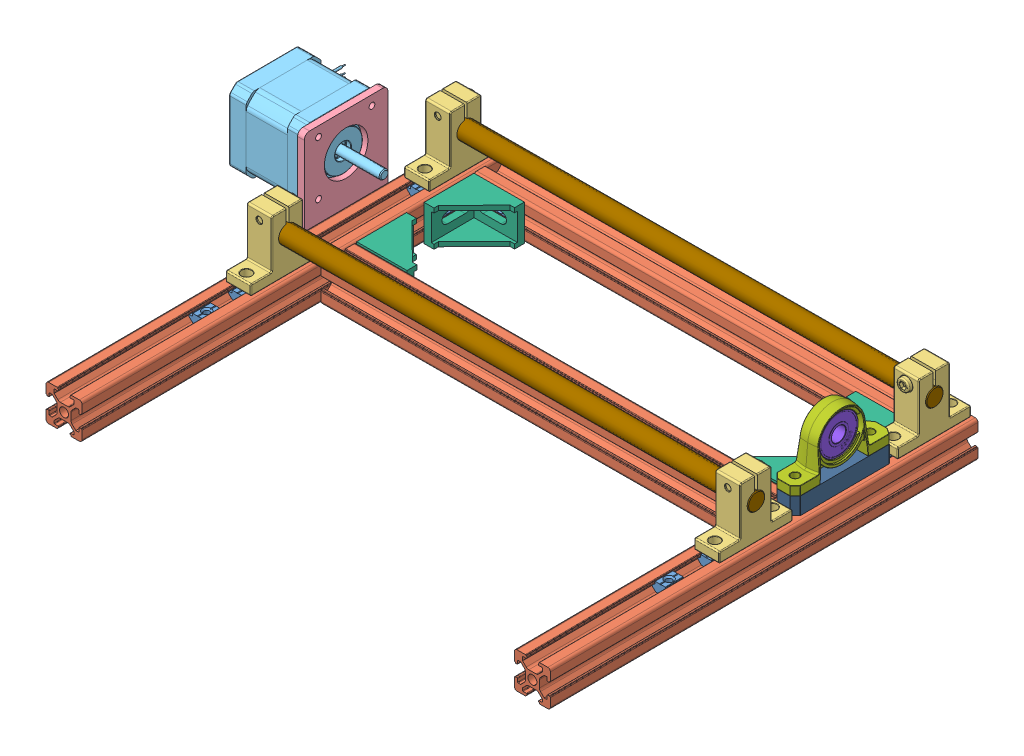
SolidWorks assembly Portal, configuration Default. Lengths in mm.
Overall size (325.5 70.93 241.56).
46 component instances, 10 part files, 48 mates.
Components (placement in the parent):
- Portal left-1: Portal left [Default] at (-77.4247 133.5164 88.3401) size (65.98 66.45 240.11) (flexible)
  - Slider T-Nut for 2020 - M4-1: Slider T-Nut for 2020 - M4 [Default] at (131.9435 -515.0191 -56.8758) x (0 -1 0) z (-0.005599 0 -0.999984) size (10 5 10)
  - Slider T-Nut for 2020 - M4-2: Slider T-Nut for 2020 - M4 [Default] at (132.0825 -515.0191 -32.0562) x (0 -1 0) z (-0.005599 0 -0.999984) size (10 5 10)
  - Slider T-Nut for 2020 - M4-3: Slider T-Nut for 2020 - M4 [Default] at (131.4239 -516.3614 -88.5284) x (0.999984 0 -0.005599) z (0.005599 0 0.999984) size (10 5 10)
  - Slider T-Nut for 2020 - M4-4: Slider T-Nut for 2020 - M4 [Default] at (131.9846 -516.3614 11.6) x (0.999984 0 -0.005599) z (0.005599 0 0.999984) size (10 5 10)
  - Slider T-Nut for 2020 - M4-5: Slider T-Nut for 2020 - M4 [Default] at (131.2447 -516.3614 -120.5279) x (0.999984 0 -0.005599) z (0.005599 0 0.999984) size (10 5 10)
  - Slider T-Nut for 2020 - M4-6: Slider T-Nut for 2020 - M4 [Default] at (141.946 -516.3614 -10.4561) x (-0.999984 0 0.005599) z (-0.005599 0 -0.999984) size (10 5 10)
  - Slider T-Nut for 2020 - M4-7: Slider T-Nut for 2020 - M4 [Default] at (141.1467 -515.0191 -92.0522) x (0 -1 0) z (0.005599 0 0.999984) size (10 5 10)
  - Slider T-Nut for 2020 - M4-8: Slider T-Nut for 2020 - M4 [Default] at (141.3587 -515.0191 -54.1911) x (0 -1 0) z (0.005599 0 0.999984) size (10 5 10)
  - 2020-2: 2020 [Default] at (136.2844 -519.7614 -121.0254) x (0.999984 0 -0.005599) z (0.005599 0 0.999984) size (20 20 240)
  - SK8 SC8UU LINEAR RAIL ORIGINAL-1: SK8 SC8UU LINEAR RAIL ORIGINAL [Valor predeterminado] at (129.4547 -493.4614 -99.5175) x (-0.005599 0 -0.999984) z (0.999984 0 -0.005599) size (41.13 32.6 13.92)
  - SK8 SC8UU LINEAR RAIL ORIGINAL-2: SK8 SC8UU LINEAR RAIL ORIGINAL [Valor predeterminado] at (130.0154 -493.4614 0.6109) x (-0.005599 0 -0.999984) z (0.999984 0 -0.005599) size (41.13 32.6 13.92)
  - Nema_17_Holder-1: Nema_17_Holder [Default] at (123.0455 -480.2144 -38.6381) x (0 -1 0) z (0.005599 0 0.999984) size (65 3.7 47)
  - nema_17_motor-1: nema_17_motor [Varsayılan] at (122.9852 -484.3114 -49.4155) x (0 -1 0) z (0.999984 0 -0.005599) size (42 58.5 65.65)
  - Slider T-Nut for 2020 - M4-9: Slider T-Nut for 2020 - M4 [Default] at (142.2497 -516.3614 43.7873) x (-0.999984 0 0.005599) z (-0.005599 0 -0.999984) size (10 5 10)
  - Slider T-Nut for 2020 - M4-10: Slider T-Nut for 2020 - M4 [Default] at (141.3398 -523.2614 -118.7171) x (-0.999984 0 0.005599) z (0.005599 0 0.999984) size (10 5 10)
- 2020-1: 2020 [Default] at (68.9155 -386.245 -22.7415) x (-0.005599 0 -0.999984) z (0.999984 0 -0.005599) size (20 20 240)
- 2020-2: 2020 [Default] at (69.3963 -386.845 63.1189) x (0.005599 0 0.999984) z (0.999984 0 -0.005599) size (20 20 240)
- Slider T-Nut for 2020 - M4-1: Slider T-Nut for 2020 - M4 [Default] at (299.9382 -381.5026 -19.335) x (0 -1 0) z (-0.999984 0 0.005599) size (10 5 10)
- Slider T-Nut for 2020 - M4-2: Slider T-Nut for 2020 - M4 [Default] at (87.9416 -381.5026 -18.1479) x (0 -1 0) z (-0.999984 0 0.005599) size (10 5 10)
- Slider T-Nut for 2020 - M4-3: Slider T-Nut for 2020 - M4 [Default] at (78.3699 -381.5026 58.3686) x (0 -1 0) z (0.999984 0 -0.005599) size (10 5 10)
- Slider T-Nut for 2020 - M4-4: Slider T-Nut for 2020 - M4 [Default] at (290.3665 -381.5026 57.1815) x (0 -1 0) z (0.999984 0 -0.005599) size (10 5 10)
- angle bracket 20x20-1: angle bracket 20x20 [Default] at (68.9715 -396.545 -12.7416) x (0.005599 0 0.999984) z (0 1 0) size (29 29 20)
- angle bracket 20x20-2: angle bracket 20x20 [Default] at (308.9678 -376.545 -14.0855) x (0.005599 0 0.999984) z (0 -1 0) size (29 29 20)
- angle bracket 20x20-3: angle bracket 20x20 [Default] at (69.3403 -376.545 53.119) x (-0.005599 0 -0.999984) z (0 -1 0) size (29 29 20)
- angle bracket 20x20-4: angle bracket 20x20 [Default] at (309.3366 -396.545 51.7752) x (-0.005599 0 -0.999984) z (0 1 0) size (29 29 20)
- Portal right-1: Portal right [Default] at (324.1953 -378.3552 77.9841) x (0.999984 0 -0.005599) z (0.005599 0 0.999984) size (20 70.33 240) (flexible)
  - 2020-1: 2020 [Default] at (-4.7118 -7.8898 -112.1535) size (20 20 240)
  - Slider T-Nut for 2020 - M4-1: Slider T-Nut for 2020 - M4 [Default] at (-9.7541 -2.9898 -24.6192) size (10 5 10)
  - Slider T-Nut for 2020 - M4-2: Slider T-Nut for 2020 - M4 [Default] at (-9.7541 -2.9898 -79.6842) size (10 5 10)
  - Slider T-Nut for 2020 - M4-3: Slider T-Nut for 2020 - M4 [Default] at (-9.4118 -3.1474 -35.2918) x (0 -1 0) z (0 0 -1) size (10 5 10)
  - Slider T-Nut for 2020 - M4-4: Slider T-Nut for 2020 - M4 [Default] at (-9.4118 -3.1474 -73.1535) x (0 -1 0) z (0 0 -1) size (10 5 10)
  - Slider T-Nut for 2020 - M4-5: Slider T-Nut for 2020 - M4 [Default] at (-9.7541 -2.9898 -66.6192) size (10 5 10)
  - Slider T-Nut for 2020 - M4-6: Slider T-Nut for 2020 - M4 [Default] at (-9.7541 -2.9898 -111.6842) size (10 5 10)
  - Slider T-Nut for 2020 - M4-7: Slider T-Nut for 2020 - M4 [Default] at (-9.7541 -2.9898 -11.5542) size (10 5 10)
  - Slider T-Nut for 2020 - M4-8: Slider T-Nut for 2020 - M4 [Default] at (-9.7541 -2.9898 20.4458) size (10 5 10)
  - Slider T-Nut for 2020 - M4-9: Slider T-Nut for 2020 - M4 [Default] at (-9.7541 -2.9898 46.1413) size (10 5 10)
  - Slider T-Nut for 2020 - M4-10: Slider T-Nut for 2020 - M4 [Default] at (-9.7541 -12.8898 -7.907) x (1 0 0) z (0 0 -1) size (10 5 10)
  - SK8 SC8UU LINEAR RAIL ORIGINAL-1: SK8 SC8UU LINEAR RAIL ORIGINAL [Valor predeterminado] at (-11.6618 18.4102 9.4458) x (0 0 -1) z (1 0 0) size (41.13 32.6 13.92)
  - SK8 SC8UU LINEAR RAIL ORIGINAL-2: SK8 SC8UU LINEAR RAIL ORIGINAL [Valor predeterminado] at (2.2382 18.4102 -90.6842) x (0 0 1) z (-1 0 0) size (41.13 32.6 13.92)
  - KP08-1: KP08 [Default] at (-4.7118 11.5602 -42.9091) x (0 0 1) z (-1 0 0) size (55 40.88 13.92)
    - KP08-2: KP08 [По умолчанию] at (2.2899 16 0) size (55 40.88 13.13)
    - 608RS-2: 608RS [Default] at (2.2899 16 -3.5) x (0.16403 0.986455 0) z (0 0 1) size (22 22 10.85)
- Shaft-1: Shaft [8mm (Default)] at (152.0285 -356.235 -11.7374) x (0.000031 0.999984 0.005599) z (0.005599 -0.005599 0.999969) size (10 274.31 10)
- Shaft-2: Shaft [8mm (Default)] at (226.8954 -356.235 87.9749) x (0.000031 -0.999984 0.005599) z (0.005599 0.005599 0.999969) size (10 274.31 10)
- stand-1: stand [Default] at (319.2562 -366.795 37.392) x (-0.005599 0 -0.999984) z (0 -1 0) size (55 13 9.45)
Mates (geometry in assembly coordinates):
- Coincident1: coincident aligned: plane of 2020-1 through (68.9615 -386.245 -14.5416) normal (0.005599 0 0.999984); plane of Slider T-Nut for 2020 - M4-1 through (299.9578 -391.345 -15.8351) normal (0.005599 0 0.999984)
- Coincident2: coincident aligned: plane of 2020-1 through (68.9615 -386.245 -14.5416) normal (0.005599 0 0.999984); plane of Slider T-Nut for 2020 - M4-2 through (87.9612 -391.345 -14.648) normal (0.005599 0 0.999984)
- Coincident3: coincident: plane of 2020-1 through (68.9155 -386.545 -22.7415) normal (0 1 0); line of Slider T-Nut for 2020 - M4-1 through (299.9646 -386.545 -14.6351) axis (-0.999984 0 0.005599)
- Coincident4: coincident: plane of 2020-1 through (68.9155 -386.545 -22.7415) normal (0 1 0); line of Slider T-Nut for 2020 - M4-2 through (87.9679 -386.545 -13.448) axis (-0.999984 0 0.005599)
- Coincident5: coincident aligned: plane of 2020-2 through (69.3504 -386.845 54.919) normal (-0.005599 0 -0.999984); plane of Slider T-Nut for 2020 - M4-3 through (78.3503 -383.345 54.8686) normal (-0.005599 0 -0.999984)
- Coincident6: coincident aligned: plane of 2020-2 through (69.3504 -386.845 54.919) normal (-0.005599 0 -0.999984); plane of Slider T-Nut for 2020 - M4-4 through (290.3469 -383.345 53.6815) normal (-0.005599 0 -0.999984)
- Coincident7: coincident: plane of 2020-2 through (69.3963 -386.545 63.1189) normal (0 -1 0); line of Slider T-Nut for 2020 - M4-4 through (290.3402 -386.545 52.4815) axis (0.999984 0 -0.005599)
- Coincident8: coincident: plane of 2020-2 through (69.3963 -386.545 63.1189) normal (0 -1 0); line of Slider T-Nut for 2020 - M4-3 through (78.3436 -386.545 53.6686) axis (0.999984 0 -0.005599)
- Coincident21: coincident aligned: plane of Portal left-1/2020-2 through (64.7596 -388.5559 -32.7184) normal (-0.005599 0 -0.999984); plane of 2020-1 through (308.8558 -377.745 -34.0852) normal (-0.005599 0 -0.999984)
- Coincident26: coincident aligned: plane of 2020-1 through (308.8558 -377.745 -34.0852) normal (-0.005599 0 -0.999984); plane of Portal right-1/2020-1 through (324.7555 -388.5559 -34.1742) normal (-0.005599 0 -0.999984)
- Coincident30: coincident aligned: plane of Portal left-1/2020-2 through (23.7593 143.0852 331.2674) normal (0 1 0); plane of 2020-2 through (269.8593 143.0852 185.7674) normal (0 1 0)
- LimitDistance1: limit distance = 9 mm aligned: plane of Slider T-Nut for 2020 - M4-3 through (78.3559 -386.545 55.8686) normal (-0.999984 0 0.005599); plane of 2020-2 through (69.4294 -384.5341 69.0188) normal (-0.999984 0 0.005599)
- LimitDistance2: limit distance = 202 mm anti-aligned: plane of Slider T-Nut for 2020 - M4-4 through (290.3525 -386.545 54.6815) normal (-0.999984 0 0.005599); plane of Slider T-Nut for 2020 - M4-3 through (88.3557 -386.545 55.8126) normal (0.999984 0 -0.005599)
- LimitDistance3: limit distance = 9 mm aligned: plane of Slider T-Nut for 2020 - M4-4 through (300.3524 -386.545 54.6255) normal (0.999984 0 -0.005599); plane of 2020-2 through (309.4256 -384.5341 67.6749) normal (0.999984 0 -0.005599)
- Coincident32: coincident anti-aligned: plane of 2020-2 through (309.3366 -378.345 51.7752) normal (-0.005599 0 -0.999984); plane of angle bracket 20x20-4 through (309.3366 -376.545 51.7752) normal (0.005599 0 0.999984)
- Slot1: slot anti-aligned: cylinder of Slider T-Nut for 2020 - M4-4 through (295.3539 -386.545 54.9035) axis (0.005599 0 0.999984) radius 1.666; plane of angle bracket 20x20-4 through (290.4326 -389.545 68.9693) normal (0 1 0); cylinder of angle bracket 20x20-4 through (300.4324 -386.545 68.9133) axis (-0.005599 0 -0.999984) radius 3
- Coincident33: coincident anti-aligned: plane of 2020-2 through (309.3366 -378.345 51.7752) normal (-0.005599 0 -0.999984); plane of angle bracket 20x20-3 through (69.3403 -396.545 53.119) normal (0.005599 0 0.999984)
- Slot2: slot anti-aligned: cylinder of Slider T-Nut for 2020 - M4-3 through (83.3572 -386.545 56.0906) axis (0.005599 0 0.999984) radius 1.666; cylinder of angle bracket 20x20-3 through (88.4357 -386.545 70.1004) axis (-0.005599 0 -0.999984) radius 3; cylinder of angle bracket 20x20-3 through (78.4359 -386.545 70.1564) axis (-0.005599 0 -0.999984) radius 3
- Coincident34: coincident aligned: plane of 2020-2 through (69.4294 -384.5341 69.0188) normal (-0.999984 0 0.005599); plane of angle bracket 20x20-3 through (69.3403 -396.545 53.119) normal (-0.999984 0 0.005599)
- Coincident35: coincident aligned: plane of 2020-2 through (309.4256 -384.5341 67.6749) normal (0.999984 0 -0.005599); plane of angle bracket 20x20-4 through (309.3366 -376.545 51.7752) normal (0.999984 0 -0.005599)
- LimitDistance4: limit distance = 9 mm aligned: plane of Slider T-Nut for 2020 - M4-2 through (77.9557 -386.545 -15.592) normal (-0.999984 0 0.005599); plane of 2020-1 through (68.8825 -388.5559 -28.6414) normal (-0.999984 0 0.005599)
- LimitDistance5: limit distance = 202 mm anti-aligned: plane of Slider T-Nut for 2020 - M4-2 through (87.9556 -386.545 -15.648) normal (0.999984 0 -0.005599); plane of Slider T-Nut for 2020 - M4-1 through (289.9524 -386.545 -16.7791) normal (-0.999984 0 0.005599)
- LimitDistance6: limit distance = 9 mm aligned: plane of Slider T-Nut for 2020 - M4-1 through (299.9522 -386.545 -16.8351) normal (0.999984 0 -0.005599); plane of 2020-1 through (308.8787 -388.5559 -29.9853) normal (0.999984 0 -0.005599)
- Coincident37: coincident anti-aligned: plane of 2020-1 through (308.9678 -394.745 -14.0855) normal (0.005599 0 0.999984); plane of angle bracket 20x20-2 through (308.9678 -396.545 -14.0855) normal (-0.005599 0 -0.999984)
- Slot3: slot anti-aligned: cylinder of Slider T-Nut for 2020 - M4-1 through (294.9509 -386.545 -17.0571) axis (-0.005599 0 -0.999984) radius 1.666; cylinder of angle bracket 20x20-2 through (289.8724 -386.545 -31.0669) axis (0.005599 0 0.999984) radius 3; cylinder of angle bracket 20x20-2 through (299.8722 -386.545 -31.1229) axis (0.005599 0 0.999984) radius 3
- Slot4: slot anti-aligned: cylinder of Slider T-Nut for 2020 - M4-2 through (82.9542 -386.545 -15.87) axis (-0.005599 0 -0.999984) radius 1.666; cylinder of angle bracket 20x20-1 through (77.8757 -386.545 -29.8798) axis (0.005599 0 0.999984) radius 3; cylinder of angle bracket 20x20-1 through (87.8756 -386.545 -29.9358) axis (0.005599 0 0.999984) radius 3
- Coincident38: coincident aligned: plane of 2020-1 through (308.8787 -388.5559 -29.9853) normal (0.999984 0 -0.005599); plane of angle bracket 20x20-2 through (308.9678 -396.545 -14.0855) normal (0.999984 0 -0.005599)
- Coincident39: coincident anti-aligned: plane of 2020-1 through (308.9678 -394.745 -14.0855) normal (0.005599 0 0.999984); plane of angle bracket 20x20-1 through (68.9715 -376.545 -12.7416) normal (-0.005599 0 -0.999984)
- Coincident40: coincident aligned: plane of 2020-1 through (68.8825 -388.5559 -28.6414) normal (-0.999984 0 0.005599); plane of angle bracket 20x20-1 through (68.9715 -376.545 -12.7416) normal (-0.999984 0 0.005599)
- Slot5: slot anti-aligned: cylinder of Portal left-1/Slider T-Nut for 2020 - M4-7 through (66 -386.545 1.2752) axis (-0.999984 0 0.005599) radius 1.666; cylinder of angle bracket 20x20-1 through (51.9902 -386.545 6.3538) axis (0.999984 0 -0.005599) radius 3; cylinder of angle bracket 20x20-1 through (51.9342 -386.545 -3.6461) axis (0.999984 0 -0.005599) radius 3
- Coincident44: coincident anti-aligned: plane of Portal left-1/2020-2 through (70.2034 -377.745 207.2549) normal (0.999984 0 -0.005599); plane of angle bracket 20x20-1 through (68.9715 -376.545 -12.7416) normal (-0.999984 0 0.005599)
- Coincident46: coincident anti-aligned: plane of Portal left-1/2020-2 through (70.2034 -377.745 207.2549) normal (0.999984 0 -0.005599); plane of angle bracket 20x20-3 through (69.3403 -396.545 53.119) normal (-0.999984 0 0.005599)
- Slot6: slot anti-aligned: cylinder of Portal left-1/Slider T-Nut for 2020 - M4-8 through (66.212 -386.545 39.1363) axis (-0.999984 0 0.005599) radius 1.666; cylinder of angle bracket 20x20-3 through (52.2022 -386.545 44.2149) axis (0.999984 0 -0.005599) radius 3; cylinder of angle bracket 20x20-3 through (52.1462 -386.545 34.215) axis (0.999984 0 -0.005599) radius 3
- Slot10: slot anti-aligned: cylinder of Portal right-1/Slider T-Nut for 2020 - M4-4 through (312.0961 -386.545 -0.1028) axis (0.999984 0 -0.005599) radius 1.666; cylinder of angle bracket 20x20-2 through (326.1619 -386.545 4.8185) axis (-0.999984 0 0.005599) radius 3; cylinder of angle bracket 20x20-2 through (326.1059 -386.545 -5.1813) axis (-0.999984 0 0.005599) radius 3
- Slot11: slot anti-aligned: cylinder of Portal right-1/Slider T-Nut for 2020 - M4-3 through (312.3081 -386.545 37.7583) axis (0.999984 0 -0.005599) radius 1.666; cylinder of angle bracket 20x20-4 through (326.3179 -386.545 32.6798) axis (-0.999984 0 0.005599) radius 3; cylinder of angle bracket 20x20-4 through (326.3739 -386.545 42.6796) axis (-0.999984 0 0.005599) radius 3
- Coincident47: coincident anti-aligned: plane of angle bracket 20x20-2 through (308.9678 -396.545 -14.0855) normal (0.999984 0 -0.005599); plane of Portal right-1/2020-1 through (310.1997 -382.345 205.911) normal (-0.999984 0 0.005599)
- LimitDistance7: limit distance = 9.8617 mm anti-aligned: plane of angle bracket 20x20-1 through (69.1283 -376.545 15.2579) normal (0.005599 0 0.999984); plane of angle bracket 20x20-3 through (69.1835 -396.545 25.1195) normal (-0.005599 0 -0.999984)
- Concentric5: concentric anti-aligned: cylinder of Portal left-1/SK8 SC8UU LINEAR RAIL ORIGINAL-1 through (81.9296 -356.235 -11.3449) axis (-0.999984 0 0.005599) radius 4.01; cylinder of Shaft-1 through (326.3331 -356.235 -12.7135) axis (0.999984 0 -0.005599) radius 5
- Coincident49: coincident aligned: plane of Portal left-1/SK8 SC8UU LINEAR RAIL ORIGINAL-1 through (51.9865 -344.645 -18.9517) normal (-0.999984 0 0.005599); plane of Shaft-1 through (52.03 -356.235 -11.1775) normal (-0.999984 0 0.005599)
- Concentric6: concentric aligned: cylinder of Portal right-1/SK8 SC8UU LINEAR RAIL ORIGINAL-2 through (296.0262 -356.235 -12.5437) axis (0.999984 0 -0.005599) radius 4.01; cylinder of Shaft-1 through (326.3331 -356.235 -12.7135) axis (0.999984 0 -0.005599) radius 5
- Concentric7: concentric anti-aligned: cylinder of Portal left-1/SK8 SC8UU LINEAR RAIL ORIGINAL-2 through (82.4902 -356.235 88.7835) axis (-0.999984 0 0.005599) radius 4.01; cylinder of Shaft-2 through (52.5907 -356.235 88.951) axis (0.999984 0 -0.005599) radius 5
- Coincident50: coincident aligned: plane of Portal left-1/SK8 SC8UU LINEAR RAIL ORIGINAL-2 through (52.5472 -344.645 81.1768) normal (-0.999984 0 0.005599); plane of Shaft-2 through (52.5907 -356.235 88.951) normal (-0.999984 0 0.005599)
- Concentric8: concentric anti-aligned: cylinder of Portal right-1/SK8 SC8UU LINEAR RAIL ORIGINAL-1 through (342.4862 -356.235 87.3277) axis (-0.999984 0 0.005599) radius 4.01; cylinder of Shaft-2 through (52.5907 -356.235 88.951) axis (0.999984 0 -0.005599) radius 5
- Concentric9: concentric anti-aligned: circle of Portal left-1/nema_17_motor-1; cylinder of Portal right-1/KP08-1/608RS-2 through (315.7562 -350.795 37.4116) axis (0.999984 0 -0.005599) radius 4
- InPlace1: in place: plane of Portal right-1/KP08-1/KP08-2 through (312.7563 -366.795 37.4284) normal (0 -1 0); plane of ? through (0 -366.795 0) normal (0 -1 0); moOrthogonalPlaneRef_w of Portal right-1/KP08-1/KP08-2 through (312.7563 -366.795 37.4284) normal (0 -1 0); plane of ? through (0 -366.795 0) normal (0 0 -1); plane of Portal right-1/KP08-1/KP08-2 through (312.7563 -366.795 37.4284) normal (0 -1 0); plane of ? through (0 -366.795 0) normal (-1 0 0); plane of Portal right-1/KP08-1/KP08-2 through (312.7563 -366.795 37.4284) normal (0 -1 0); unknown of stand-1
- Coincident51: coincident aligned: plane of Portal right-1/KP08-1/KP08-2; plane of stand-1
- Coincident52: coincident aligned: moOrthogonalPlaneRef_w of Portal right-1/KP08-1/KP08-2 through (319.2562 -366.795 37.392) normal (0.999984 0 -0.005599); plane of stand-1 through (319.2562 -366.795 37.392) normal (0.999984 0 -0.005599)
- Coincident53: coincident anti-aligned: moOrthogonalPlaneRef_w of Portal right-1/KP08-1/KP08-2 through (319.2562 -366.795 37.392) normal (0.005599 0 0.999984); plane of stand-1 through (319.2562 -366.795 37.392) normal (-0.005599 0 -0.999984)
